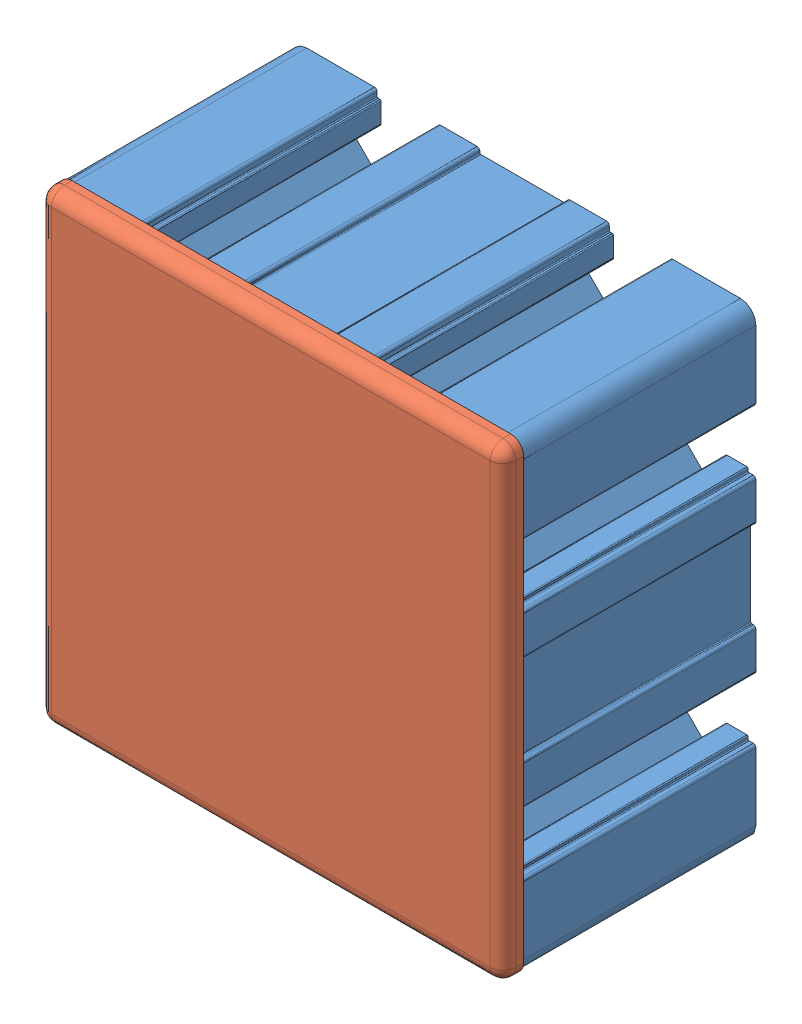
SolidWorks assembly Заглушка90х90СБ, configuration По умолчанию. Lengths in mm.
Overall size (90 90 49).
2 component instances, 2 part files, 6 mates.
Components (placement in the parent):
- 90х90 заглушка-1: 90х90 заглушка [По умолчанию] at origin size (90 90 45)
- Заглушка торцевая 90х90-1: Заглушка торцевая 90х90 [По умолчанию] at (-4.9414 12.7231 47) x (0 0 -1) z (1 0 0) size (12 90 90)
Mates (geometry in assembly coordinates):
- Совпадение2: coincident: point of 90х90 заглушка-1
- Параллельность1: parallel anti-aligned: plane of 90х90 заглушка-1 through (0 -32.2769 45) normal (0 -1 0)
- Совпадение4: coincident anti-aligned: plane of 90х90 заглушка-1 through (0 0 0) normal (0 0 -1)
- Совпадение5: coincident anti-aligned: plane of 90х90 заглушка-1 through (0 0 45) normal (0 0 1); plane of Заглушка торцевая 90х90-1 through (-49.9414 -32.2769 45) normal (0 0 -1)
- Совпадение6: coincident aligned: plane of 90х90 заглушка-1 through (40.0586 0 45) normal (1 0 0); plane of Заглушка торцевая 90х90-1 through (40.0586 55.2231 46.5) normal (1 0 0)
- Совпадение7: coincident aligned: plane of 90х90 заглушка-1 through (0 57.7231 45) normal (0 1 0); plane of Заглушка торцевая 90х90-1 through (-49.9414 57.7231 46.5) normal (0 1 0)
